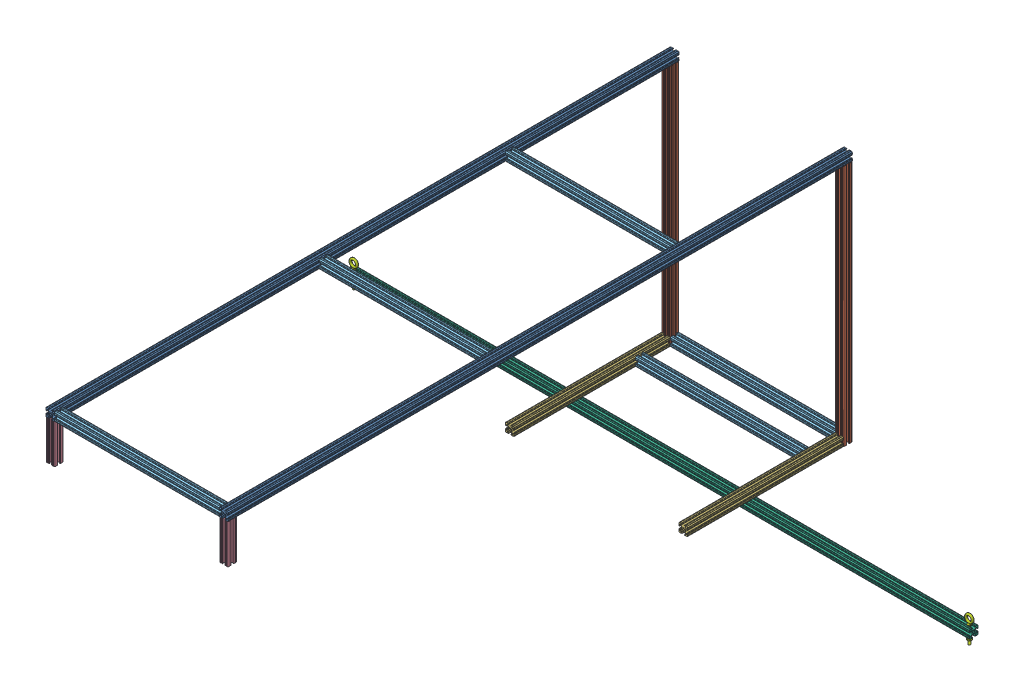
SolidWorks assembly Retraction Frame, configuration Default. Lengths in mm.
Overall size (1828.8 787.97 1828.8).
16 component instances, 7 part files, 47 mates.
Components (placement in the parent):
- 8020 -1inch - 5 ft 0 in-1: 8020 -1inch - 5 ft 0 in [47065T122] at (641.4215 936.2006 1437.8545) size (25.4 25.4 1828.8)
- 8020 -1inch - 2 ft 4 inches-1: 8020 -1inch - 2 ft 4 inches [47065T122] at (641.4215 567.9006 536.1545) x (1 0 0) z (0 -1 0) size (25.4 25.4 711.2)
- 8020 -1inch - 1 ft 6 in-1: 8020 -1inch - 1 ft 6 in [47065T122] at (641.4215 225.0006 777.4545) size (25.4 25.4 457.2)
- 8020 -1inch - 0 ft 4.5 in-1: 8020 -1inch - 0 ft 4.5 in [47065T122] at (641.4215 866.3506 2339.5545) x (1 0 0) z (0 -1 0) size (25.4 25.4 114.3)
- 8020 -1inch - 0 ft 4.5 in-2: 8020 -1inch - 0 ft 4.5 in [47065T122] at (133.4215 866.3506 2339.5545) x (1 0 0) z (0 -1 0) size (25.4 25.4 114.3)
- 8020 -1inch - 1 ft 6 in-2: 8020 -1inch - 1 ft 6 in [47065T122] at (133.4215 225.0006 777.4545) size (25.4 25.4 457.2)
- 8020 -1inch - 2 ft 4 inches-2: 8020 -1inch - 2 ft 4 inches [47065T122] at (133.4215 567.9006 536.1545) x (1 0 0) z (0 -1 0) size (25.4 25.4 711.2)
- 8020 -1inch - 5 ft 0 in-2: 8020 -1inch - 5 ft 0 in [47065T122] at (133.4215 936.2006 1437.8545) size (25.4 25.4 1828.8)
- 8020 -1inch - 1 ft 7 in-2: 8020 -1inch - 1 ft 7 in [47065T122] at (387.4215 225.0006 536.1545) x (0 0 1) z (-1 0 0) size (25.4 25.4 482.6)
- 8020 -1inch - 1 ft 7 in-3: 8020 -1inch - 1 ft 7 in [47065T122] at (387.4215 225.0006 637.7545) x (0 0 1) z (-1 0 0) size (25.4 25.4 482.6)
- 8020 -1inch - 1 ft 7 in-4: 8020 -1inch - 1 ft 7 in [47065T122] at (387.4215 936.2006 1018.7545) x (0 0 1) z (-1 0 0) size (25.4 25.4 482.6)
- 8020 -1inch - 1 ft 7 in-5: 8020 -1inch - 1 ft 7 in [47065T122] at (387.4215 936.2006 2339.5545) x (0 0 1) z (-1 0 0) size (25.4 25.4 482.6)
- 8020 -1inch - 1 ft 7 in-6: 8020 -1inch - 1 ft 7 in [47065T122] at (387.4215 936.2006 1564.8545) x (0 0 1) z (-1 0 0) size (25.4 25.4 482.6)
- 8020 -1inch - 6 feet with guide line holes-1: 8020 -1inch - 6 feet with guide line holes [47065T122] at (387.4215 199.6006 815.5545) x (0 0 -1) z (1 0 0) size (25.4 25.4 1828.8)
- 1.5 inch lifting eye-1: 1.5 inch lifting eye [3032T41] at (1289.1215 228.1756 815.5545) size (25.4 79.95 12.83)
- 1.5 inch lifting eye-2: 1.5 inch lifting eye [3032T41] at (-514.2785 228.1756 815.5545) size (25.4 79.95 12.83)
Mates (geometry in assembly coordinates):
- Coincident1: coincident anti-aligned: plane of 8020 -1inch - 5 feet-1 through (647.7546 923.5006 2352.2545) normal (0 -1 0); plane of 8020 -1inch - 2 ft 4 inches-1 through (635.0051 923.5006 526.7447) normal (0 1 0)
- Coincident2: coincident aligned: plane of 8020 -1inch - 5 feet-1 through (635.0051 926.7908 523.4545) normal (0 0 -1); plane of 8020 -1inch - 2 ft 4 inches-1 through (647.7546 212.3006 523.4545) normal (0 0 -1)
- Coincident3: coincident aligned: plane of 8020 -1inch - 5 feet-1 through (654.1215 926.6502 2352.2545) normal (1 0 0); plane of 8020 -1inch - 2 ft 4 inches-1 through (654.1215 212.3006 526.6041) normal (1 0 0)
- Coincident4: coincident anti-aligned: plane of 8020 -1inch - 2 ft 4 inches-1 through (650.9719 212.3006 548.8545) normal (0 0 1); plane of 8020 -1inch - 1 ft 6 inches-1 through (635.0051 215.5908 548.8545) normal (0 0 -1)
- Coincident5: coincident anti-aligned: plane of 8020 -1inch - 2 ft 4 inches-1 through (650.9719 212.3006 548.8545) normal (0 0 1); plane of 8020 -1inch - 1 ft 6 inches-1 through (635.0051 215.5908 548.8545) normal (0 0 -1)
- Coincident6: coincident aligned: plane of 8020 -1inch - 2 ft 4 inches-1 through (635.0051 212.3006 526.7447) normal (0 -1 0); plane of 8020 -1inch - 1 ft 6 inches-1 through (647.7546 212.3006 1006.0545) normal (0 -1 0)
- Coincident7: coincident aligned: plane of 8020 -1inch - 2 ft 4 inches-1 through (654.1215 212.3006 542.4876) normal (1 0 0); plane of 8020 -1inch - 1 ft 6 inches-1 through (654.1215 215.4502 1006.0545) normal (1 0 0)
- Coincident8: coincident anti-aligned: plane of 8020 -1inch - 5 feet-1 through (647.7546 923.5006 2352.2545) normal (0 -1 0); plane of 8020 -1inch - 0 ft 5 in-1 through (635.0051 923.5006 2330.1447) normal (0 1 0)
- Coincident9: coincident aligned: plane of 8020 -1inch - 5 feet-1 through (654.1215 926.6502 2352.2545) normal (1 0 0); plane of 8020 -1inch - 5 inches-1 through (654.1215 809.2006 2330.0041) normal (1 0 0)
- Coincident10: coincident aligned: plane of 8020 -1inch - 5 feet-1 through (635.0051 926.7908 2352.2545) normal (0 0 1); plane of 8020 -1inch - 5 inches-1 through (650.9719 809.2006 2352.2545) normal (0 0 1)
- Coincident11: coincident anti-aligned: plane of 8020 -1inch - 0 ft 5 in-2 through (127.0051 923.5006 2330.1447) normal (0 1 0); plane of 8020 -1inch - 5 ft 0 in-2 through (139.7546 923.5006 2352.2545) normal (0 -1 0)
- Coincident12: coincident aligned: plane of 8020 -1inch - 0 ft 5 in-2 through (142.9719 809.2006 2352.2545) normal (0 0 1); plane of 8020 -1inch - 5 ft 0 in-2 through (127.0051 926.7908 2352.2545) normal (0 0 1)
- Coincident13: coincident aligned: plane of 8020 -1inch - 0 ft 5 in-2 through (146.1215 809.2006 2330.0041) normal (1 0 0); plane of 8020 -1inch - 5 ft 0 in-2 through (146.1215 926.6502 2352.2545) normal (1 0 0)
- Coincident14: coincident anti-aligned: plane of 8020 -1inch - 1 ft 6 inches-2 through (127.0051 215.5908 548.8545) normal (0 0 -1); plane of 8020 -1inch - 2 ft 3 inches-2 through (142.9719 212.3006 548.8545) normal (0 0 1)
- Coincident15: coincident anti-aligned: plane of 8020 -1inch - 1 ft 6 inches-2 through (127.0051 215.5908 548.8545) normal (0 0 -1); plane of 8020 -1inch - 2 ft 3 inches-2 through (142.9719 212.3006 548.8545) normal (0 0 1)
- Coincident16: coincident aligned: plane of 8020 -1inch - 2 ft 3 inches-2 through (146.1215 212.3006 526.6041) normal (1 0 0); plane of 8020 -1inch - 5 ft 0 in-2 through (146.1215 926.6502 2352.2545) normal (1 0 0)
- Coincident17: coincident anti-aligned: plane of 8020 -1inch - 2 ft 3 inches-2 through (127.0051 923.5006 526.7447) normal (0 1 0); plane of 8020 -1inch - 5 ft 0 in-2 through (139.7546 923.5006 2352.2545) normal (0 -1 0)
- Coincident18: coincident aligned: plane of 8020 -1inch - 1 ft 6 inches-2 through (146.1215 215.4502 1006.0545) normal (1 0 0); plane of 8020 -1inch - 2 ft 3 inches-2 through (146.1215 212.3006 542.4876) normal (1 0 0)
- Coincident19: coincident aligned: plane of 8020 -1inch - 1 ft 6 inches-2 through (139.7546 212.3006 1006.0545) normal (0 -1 0); plane of 8020 -1inch - 2 ft 3 inches-2 through (127.0051 212.3006 526.7447) normal (0 -1 0)
- Coincident20: coincident aligned: plane of 8020 -1inch - 2 ft 3 inches-2 through (139.7546 212.3006 523.4545) normal (0 0 -1); plane of 8020 -1inch - 5 ft 0 in-2 through (127.0051 926.7908 523.4545) normal (0 0 -1)
- Coincident24: coincident anti-aligned: plane of 8020 -1inch - 2 ft 3 inches-1 through (628.7215 212.3006 529.8215) normal (-1 0 0); plane of 8020 -1inch - 1 ft 7 in-2 through (628.7215 215.5908 529.7381) normal (1 0 0)
- Coincident25: coincident aligned: plane of 8020 -1inch - 2 ft 3 inches-1 through (631.8711 212.3006 523.4545) normal (0 0 -1); plane of 8020 -1inch - 1 ft 7 in-2 through (146.1215 218.6675 523.4545) normal (0 0 -1)
- Coincident26: coincident aligned: plane of 8020 -1inch - 2 ft 3 inches-1 through (635.0051 212.3006 526.7447) normal (0 -1 0); plane of 8020 -1inch - 1 ft 7 in-2 through (146.1215 212.3006 526.6041) normal (0 -1 0)
- Coincident27: coincident anti-aligned: plane of 8020 -1inch - 2 ft 3 inches-2 through (146.1215 212.3006 526.6041) normal (1 0 0); plane of 8020 -1inch - 1 ft 7 in-2 through (146.1215 215.5908 529.7381) normal (-1 0 0)
- Coincident28: coincident aligned: plane of 8020 -1inch - 2 ft 3 inches-2 through (127.0051 212.3006 526.7447) normal (0 -1 0); plane of 8020 -1inch - 1 ft 7 in-2 through (146.1215 212.3006 526.6041) normal (0 -1 0)
- Coincident29: coincident aligned: plane of 8020 -1inch - 2 ft 3 inches-2 through (123.8711 212.3006 523.4545) normal (0 0 -1); plane of 8020 -1inch - 1 ft 7 in-2 through (146.1215 218.6675 523.4545) normal (0 0 -1)
- Coincident30: coincident anti-aligned: plane of 8020 -1inch - 1 ft 6 inches-1 through (628.7215 218.6675 1006.0545) normal (-1 0 0); plane of 8020 -1inch - 1 ft 7 in-3 through (628.7215 215.5908 631.3381) normal (1 0 0)
- Coincident31: coincident aligned: plane of 8020 -1inch - 1 ft 6 inches-1 through (631.8711 212.3006 1006.0545) normal (0 -1 0); plane of 8020 -1inch - 1 ft 7 in-3 through (146.1215 212.3006 628.2041) normal (0 -1 0)
- Distance2: distance = 76.2 mm anti-aligned: plane of 8020 -1inch - 1 ft 7 in-2 through (146.1215 215.4502 548.8545) normal (0 0 1); plane of 8020 -1inch - 1 ft 7 in-3 through (146.1215 218.6675 625.0545) normal (0 0 -1)
- Coincident33: coincident anti-aligned: plane of 8020 -1inch - 5 ft 0 in-1 through (628.7215 945.751 2352.2545) normal (-1 0 0); plane of 8020 -1inch - 1 ft 7 in-4 through (628.7215 926.7908 1012.3381) normal (1 0 0)
- Coincident34: coincident aligned: plane of 8020 -1inch - 5 ft 0 in-1 through (631.8711 923.5006 2352.2545) normal (0 -1 0); plane of 8020 -1inch - 1 ft 7 in-4 through (146.1215 923.5006 1009.2041) normal (0 -1 0)
- Coincident35: coincident anti-aligned: plane of 8020 -1inch - 1 ft 6 inches-2 through (127.0051 215.5908 1006.0545) normal (0 0 1); plane of 8020 -1inch - 1 ft 7 in-4 through (146.1215 945.751 1006.0545) normal (0 0 -1)
- Coincident36: coincident anti-aligned: plane of 8020 -1inch - 5 ft 0 in-2 through (146.1215 942.5337 2352.2545) normal (1 0 0); plane of 8020 -1inch - 1 ft 7 in-5 through (146.1215 926.7908 2333.1381) normal (-1 0 0)
- Coincident38: coincident aligned: plane of 8020 -1inch - 5 ft 0 in-2 through (142.9719 948.9006 2352.2545) normal (0 1 0); plane of 8020 -1inch - 1 ft 7 in-5 through (146.1215 948.9006 2349.105) normal (0 1 0)
- Coincident39: coincident aligned: plane of 8020 -1inch - 5 ft 0 in-2 through (127.0051 926.7908 2352.2545) normal (0 0 1); plane of 8020 -1inch - 1 ft 7 in-5 through (146.1215 942.5337 2352.2545) normal (0 0 1)
- Coincident40: coincident anti-aligned: plane of 8020 -1inch - 5 ft 0 in-2 through (146.1215 942.5337 2352.2545) normal (1 0 0); plane of 8020 -1inch - 1 ft 7 in-6 through (146.1215 926.7908 1558.4381) normal (-1 0 0)
- Coincident41: coincident aligned: plane of 8020 -1inch - 5 ft 0 in-2 through (142.9719 948.9006 2352.2545) normal (0 1 0); plane of 8020 -1inch - 1 ft 7 in-6 through (146.1215 948.9006 1558.5214) normal (0 1 0)
- Distance3: distance = 520.7 mm anti-aligned: plane of 8020 -1inch - 1 ft 7 in-6 through (146.1215 945.751 1552.1545) normal (0 0 -1); plane of 8020 -1inch - 1 ft 7 in-4 through (146.1215 942.5337 1031.4545) normal (0 0 1)
- Distance4: distance = 203.2 mm anti-aligned: plane of 8020 -1inch - 6 feet with guide line holes-1 through (1301.8215 205.9337 802.8545) normal (0 0 -1); plane of 8020 -1inch - 1 ft 6 in-1 through (635.0051 215.5908 1006.0545) normal (0 0 1)
- Coincident46: coincident anti-aligned: plane of 8020 -1inch - 1 ft 6 in-1 through (647.7546 212.3006 1006.0545) normal (0 -1 0); plane of 8020 -1inch - 6 feet with guide line holes-1 through (1301.8215 212.3006 806.0041) normal (0 1 0)
- Distance5: distance = 647.7 mm aligned: plane of 8020 -1inch - 6 feet with guide line holes-1 through (1301.8215 190.1908 821.9709) normal (1 0 0); plane of 8020 -1inch - 1 ft 6 in-1 through (654.1215 215.4502 1006.0545) normal (1 0 0)
- Concentric1: concentric aligned: cylinder of 8020 -1inch - 6 feet with guide line holes-1 through (1289.1215 186.9006 815.5545) axis (0 1 0) radius 3.175; cylinder of 1.5 inch lifting eye-1 through (1289.1215 161.5006 815.5545) axis (0 1 0) radius 3.175
- Coincident48: coincident anti-aligned: plane of 8020 -1inch - 6 feet with guide line holes-1 through (1301.8215 212.3006 806.0041) normal (0 1 0); plane of 1.5 inch lifting eye-1 through (1284.359 212.3006 815.5545) normal (0 -1 0)
- Parallel2: parallel aligned: plane of 8020 -1inch - 6 feet with guide line holes-1 through (1301.8215 190.1908 821.9709) normal (1 0 0); plane of 1.5 inch lifting eye-1 through (1294.6778 174.2006 812.3466) normal (1 0 0)
- Concentric2: concentric aligned: cylinder of 8020 -1inch - 6 feet with guide line holes-1 through (-514.2785 186.9006 815.5545) axis (0 1 0) radius 3.175; cylinder of 1.5 inch lifting eye-2 through (-514.2785 161.5006 815.5545) axis (0 1 0) radius 3.175
- Coincident50: coincident anti-aligned: plane of 8020 -1inch - 6 feet with guide line holes-1 through (1301.8215 212.3006 806.0041) normal (0 1 0); plane of 1.5 inch lifting eye-2 through (-519.041 212.3006 815.5545) normal (0 -1 0)
- Parallel3: parallel aligned: plane of 8020 -1inch - 6 feet with guide line holes-1 through (-526.9785 190.1908 821.9709) normal (-1 0 0); plane of 1.5 inch lifting eye-2 through (-519.8347 174.2006 818.7624) normal (-1 0 0)
